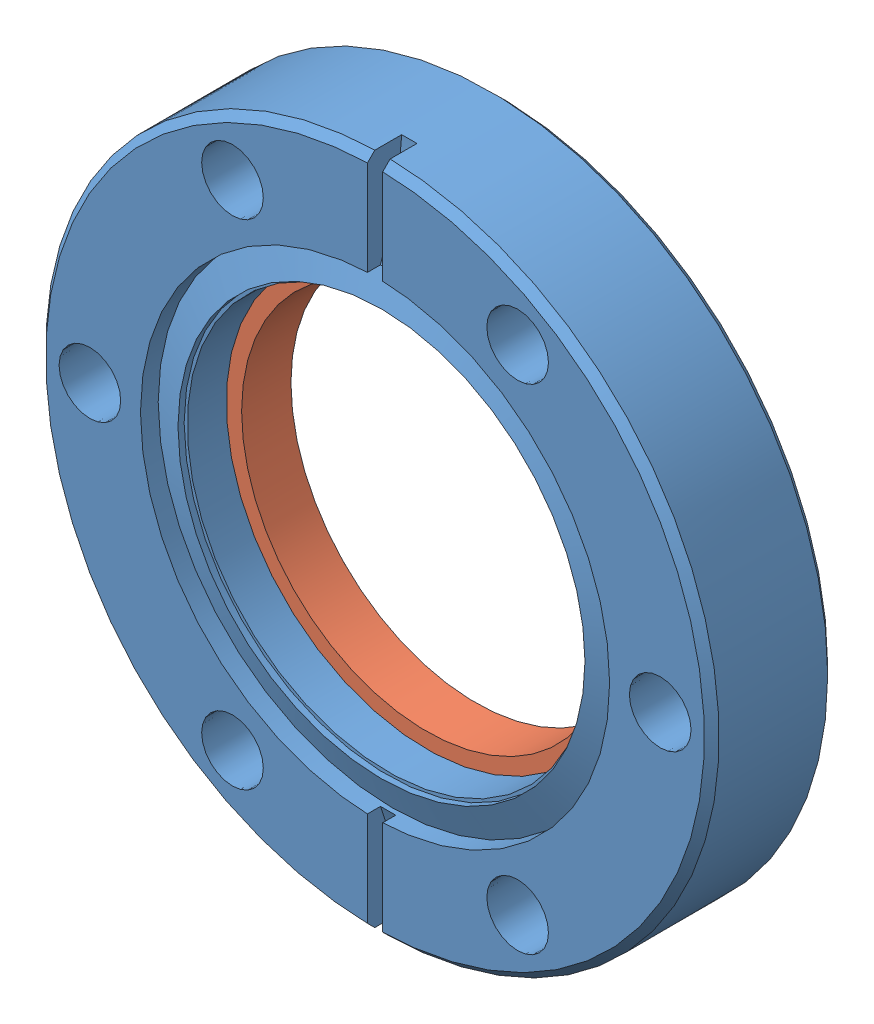
SolidWorks assembly window 275 SW, configuration Default. Lengths in mm.
Overall size (69.34 69.34 12.7).
2 component instances, 2 part files, 0 mates.
Components (placement in the parent):
- 130094_1-1: 130094_1 [Default] at (-8.8308 6.0802 -6.35) size (69.34 69.34 12.7)
- glass_1-1: glass_1 [Default] at (-8.8308 6.0802 1.0414) x (-1 0 0) z (0 0 -1) size (44.7 44.7 5.08)
